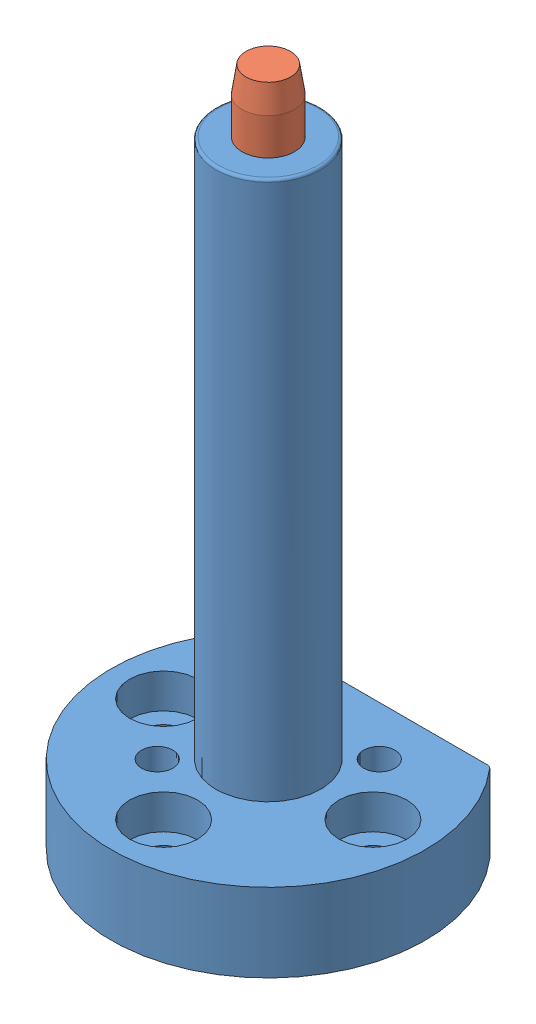
SolidWorks assembly assemb_pino_posi_t2, configuration Default. Lengths in mm.
Overall size (60 130.34 49.5).
3 component instances, 3 part files, 4 mates.
Components (placement in the parent):
- suporte_posi_t2-1: suporte_posi_t2 [Default] at (49.445 2.9845 87.4507) size (60 118 49.5)
- pino_t2-1: pino_t2 [Default] at (49.445 54.9845 87.4507) size (14.5 78 14.5)
- mola_posicionamento-1: mola_posicionamento [Default] at (49.445 54.9845 87.4507) x (-0.837169 0 -0.546944) z (-0.546944 0 0.837169) size (14.66 52.36 14.64)
Mates (geometry in assembly coordinates):
- Concentric1: concentric anti-aligned: cylinder of suporte_posi_t2-1 through (49.445 120.9845 87.4507) axis (0 -1 0) radius 10; cylinder of pino_t2-1 through (49.445 132.9845 87.4507) axis (0 1 0) radius 5
- Coincident1: coincident anti-aligned: plane of suporte_posi_t2-1 through (49.445 59.9845 87.4507) normal (0 -1 0); plane of pino_t2-1 through (56.695 59.9845 87.4507) normal (0 1 0)
- Concentric2: concentric aligned: cylinder of suporte_posi_t2-1 through (49.445 59.9845 87.4507) axis (0 -1 0) radius 7.25; circle of mola_posicionamento-1
- Coincident2: coincident aligned: plane of pino_t2-1 through (49.445 54.9845 87.4507) normal (0 -1 0); circle of mola_posicionamento-1
